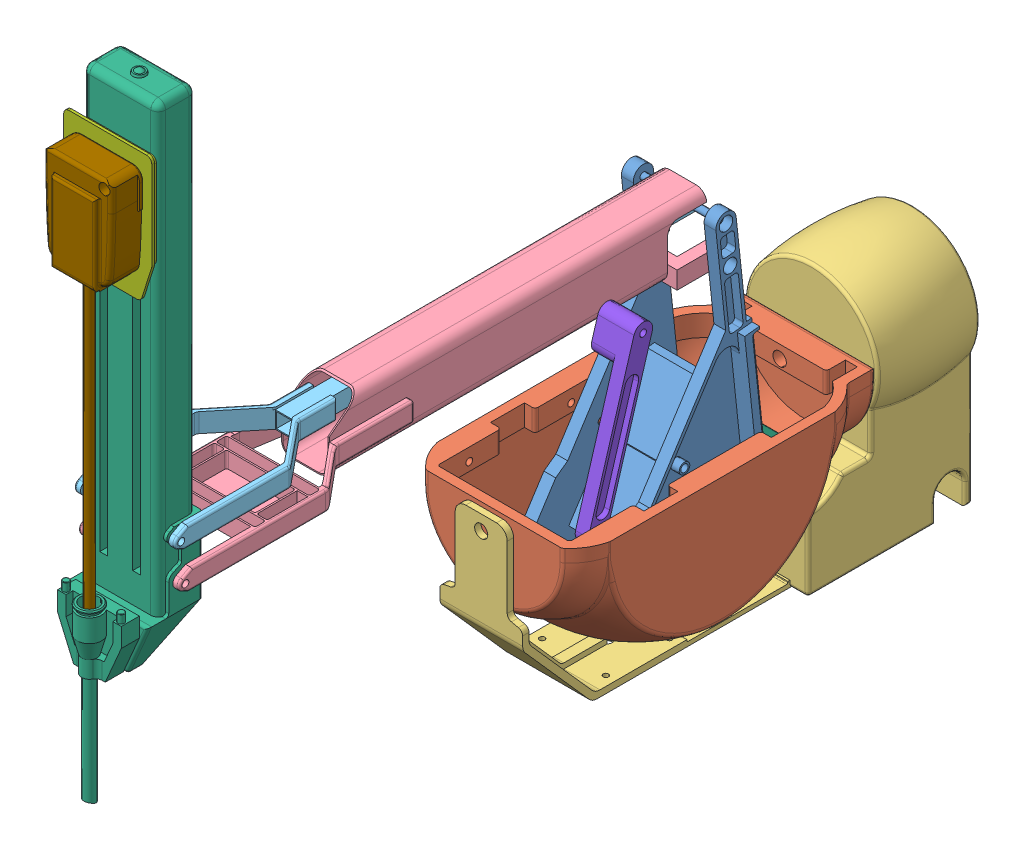
SolidWorks assembly PSM, configuration Default. Lengths in mm.
Overall size (163.88 691.06 791.55).
16 component instances, 15 part files, 45 mates.
Components (placement in the parent):
- pitch_back-1: pitch_back [Default] at (44.5 152.4 259.8) x (0 0.106301 -0.994334) z (1 0 0) size (154.33 284.37 103)
- outer_yaw-1: outer_yaw [Default] at (0 152.4 394.8) x (0 0 -1) z (1 0 0) size (296.1 145.6 163.88)
- Base-1: Base [Default] at (0 152.4 406.8) x (0 0 -1) z (1 0 0) size (406.8 219.4 134)
- pitch_bottom-1: pitch_bottom [Default] at (0 296.1053 216.8026) x (0 0 -1) z (1 0 0) size (530 58.09 95)
- pitch_top-1: pitch_top [Default] at (0 332.3985 220.6826) x (0 0 -1) z (1 0 0) size (530 18 95)
- pitch_end-1: pitch_end [Default] at (-35.75 687.2053 710.8026) x (1 0 0) z (0 -1 0) size (77.5 79.5 575.26)
- tool_holder-1: tool_holder [Default] at (-41.5 564.2053 756.0526) size (83 122 11.35)
- pitch_front-1: pitch_front [Default] at (46.5 152.4 355.8) x (0 0.958036 -0.286649) z (1 0 0) size (168 18 34)
- Tool_main-1: Tool_main [Default] at (0 543.6953 775.8026) x (1 0 0) z (0 -1 0) size (68.49 33 464)
- Tool_Wrists_Link_1-1: Tool_Wrists_Link_1 [Default] at (0 176.3953 775.8026) x (1 0 0) z (0 -1 0) size (8.32 8.32 11)
- Tool_Wrists_Shaft_Link_1_2-1: Tool_Wrists_Shaft_Link_1_2 [Default] at (3.9 167.2953 775.8026) x (0 -0.980722 0.195408) z (-1 0 0) size (1.3 1.3 8.02)
- Tool_Wristis_Small_Clip_Applier_Link_2-1: Tool_Wristis_Small_Clip_Applier_Link_2 [Default] at (0 162.1953 772.6026) x (0 1 0) z (0 0 1) size (13.22 7.35 6.88)
- Tool_Wristis_Small_Clip_Applier_shaft_Link_2_3-1: Tool_Wristis_Small_Clip_Applier_shaft_Link_2_3 [Default] at (0 158.1953 773.2026) x (0.959628 0.281272 0) z (0 0 1) size (1.3 1.3 5)
- Tool_Wristis_Small_Clip_Applier_Link_3-1: Tool_Wristis_Small_Clip_Applier_Link_3 [Default] at (0 158.1953 775.5026) x (1 0 0) z (0 0 -1) size (5 13.1 2.29)
- Tool_Wristis_Small_Clip_Applier_Link_3-2: Tool_Wristis_Small_Clip_Applier_Link_3 [Default] at (0 158.1953 776.0026) x (-1 0 0) z (0 0 1) size (5 13.1 2.29)
- counterweight-1: counterweight [Default] at (44.5 98.29 154.4714) x (0 -0.106301 0.994334) z (-1 0 0) size (25.4 25.4 89)
Mates (geometry in assembly coordinates):
- Concentric19: concentric aligned: cylinder of outer_yaw-1 through (0 152.4 80.7395) axis (0 0 1) radius 6.35; cylinder of Base-1 through (0 152.4 51.2) axis (0 0 1) radius 6.2
- Distance5: distance = 6 mm anti-aligned: plane of outer_yaw-1 through (0 152.4 394.8) normal (0 0 1); plane of Base-1 through (-56 152.4 400.8) normal (0 0 -1)
- Concentric21: concentric anti-aligned: cylinder of pitch_back-1 through (-44.5 296.1053 216.8026) axis (1 0 0) radius 6.35; cylinder of pitch_bottom-1 through (47.5 296.1053 216.8026) axis (-1 0 0) radius 3.175
- Concentric25: concentric aligned: cylinder of pitch_back-1 through (-44.5 332.3985 220.6826) axis (1 0 0) radius 6.35; cylinder of pitch_top-1 through (-47.5 332.3985 220.6826) axis (1 0 0) radius 3.175
- Concentric27: concentric anti-aligned: cylinder of pitch_back-1 through (-44.5 152.4 259.8) axis (1 0 0) radius 3.5; cylinder of outer_yaw-1 through (56.25 152.4 259.8) axis (-1 0 0) radius 3.175
- Coincident14: coincident anti-aligned: plane of Base-1 through (-56 152.4 0) normal (0 0 -1); plane of assembly through (0 0 0) normal (0 0 1)
- Coincident15: coincident anti-aligned: plane of Base-1 through (-56 0 406.8) normal (0 -1 0); plane of assembly through (0 0 0) normal (0 1 0)
- Coincident16: coincident aligned: plane of Base-1 through (0 152.4 406.8) normal (1 0 0); plane of assembly through (0 0 0) normal (1 0 0)
- Coincident17: coincident aligned: plane of pitch_back-1 through (0 152.4 259.8) normal (1 0 0); plane of outer_yaw-1 through (0 152.4 394.8) normal (1 0 0)
- Coincident18: coincident aligned: plane of pitch_back-1 through (0 152.4 259.8) normal (1 0 0); plane of pitch_bottom-1 through (0 296.1053 216.8026) normal (1 0 0)
- Coincident19: coincident aligned: plane of pitch_back-1 through (0 152.4 259.8) normal (1 0 0); plane of pitch_top-1 through (0 332.3985 220.6826) normal (1 0 0)
- Concentric29: concentric anti-aligned: cylinder of pitch_bottom-1 through (47.5 296.1053 732.8026) axis (-1 0 0) radius 3.175; cylinder of pitch_end-1 through (-43.2472 296.1053 732.8026) axis (1 0 0) radius 1.59
- Concentric30: concentric aligned: cylinder of pitch_top-1 through (-47.5 332.3985 736.6826) axis (1 0 0) radius 3.175; cylinder of pitch_end-1 through (-43.2472 332.3985 736.6826) axis (1 0 0) radius 1.5875
- Coincident20: coincident aligned: plane of pitch_bottom-1 through (0 296.1053 216.8026) normal (1 0 0); plane of pitch_end-1 through (0 687.2053 710.8026) normal (1 0 0)
- Distance7: distance = 0.4 mm anti-aligned: plane of tool_holder-1 through (-41.5 564.2053 747.2026) normal (0 0 -1); plane of pitch_end-1 through (-35.75 268.1053 746.8026) normal (0 0 1)
- Coincident21: coincident aligned: plane of pitch_end-1 through (0 687.2053 710.8026) normal (1 0 0); plane of tool_holder-1 through (0 564.2053 756.0526) normal (1 0 0)
- Concentric31: concentric aligned: cylinder of outer_yaw-1 through (56.25 152.4 355.8) axis (-1 0 0) radius 3.175; cylinder of pitch_front-1 through (58.5 152.4 355.8) axis (-1 0 0) radius 3.175
- Concentric33: concentric aligned: cylinder of pitch_bottom-1 through (47.5 296.1053 312.8026) axis (-1 0 0) radius 3.175; cylinder of pitch_front-1 through (58.5 296.1053 312.8026) axis (-1 0 0) radius 3.175
- Distance8: distance = 2 mm anti-aligned: plane of pitch_bottom-1 through (22.5 296.1053 216.8026) normal (1 0 0); plane of pitch_front-1 through (24.5 296.1053 312.8026) normal (-1 0 0)
- Concentric1: concentric: circle of Tool_main-1; circle of Tool_Wrists_Link_1-1
- Distance12: distance = 0.5 mm: plane of Tool_main-1 through (0 176.8953 775.8026) normal (0 -1 0); plane of Tool_Wrists_Link_1-1 through (0 176.3953 775.8026) normal (0 1 0)
- Parallel1: parallel: plane of Tool_main-1; plane of Tool_Wristis_Small_Clip_Applier_Link_3-1
- Concentric2: concentric anti-aligned: circle of Tool_Wrists_Link_1-1; cylinder of Tool_Wrists_Shaft_Link_1_2-1 through (-4.12 167.2953 775.8026) axis (1 0 0) radius 0.65
- Concentric3: concentric aligned: circle of Tool_Wrists_Link_1-1; cylinder of Tool_Wristis_Small_Clip_Applier_Link_2-1 through (3.6753 167.2953 775.8026) axis (-1 0 0) radius 0.65
- Distance2: distance = 7.1 mm aligned: plane of Tool_Wrists_Shaft_Link_1_2-1 through (3.9 167.2953 775.8026) normal (1 0 0); plane of Tool_Wrists_Link_1-1 through (-3.2 164.5379 771.6426) normal (1 0 0)
- Distance3: distance = 4.5 mm aligned: plane of Tool_Wristis_Small_Clip_Applier_shaft_Link_2_3-1 through (0 158.1953 773.2026) normal (0 0 -1); plane of Tool_Wristis_Small_Clip_Applier_Link_2-1 through (3.6753 156.1953 777.7026) normal (0 0 -1)
- Concentric4: concentric aligned: circle of Tool_Wristis_Small_Clip_Applier_Link_2-1; circle of Tool_Wristis_Small_Clip_Applier_Link_3-2
- Distance9: distance = 0.05 mm anti-aligned: plane of Tool_Wristis_Small_Clip_Applier_Link_3-2 through (0 158.1953 777.6526) normal (0 0 1); plane of Tool_Wristis_Small_Clip_Applier_Link_2-1 through (3.6753 156.1953 777.7026) normal (0 0 -1)
- Concentric5: concentric anti-aligned: circle of Tool_Wristis_Small_Clip_Applier_Link_2-1; circle of Tool_Wristis_Small_Clip_Applier_Link_3-1
- Distance13: distance = 0.05 mm anti-aligned: plane of Tool_Wristis_Small_Clip_Applier_Link_3-1 through (0 158.1953 773.8526) normal (0 0 -1); plane of Tool_Wristis_Small_Clip_Applier_Link_2-1 through (3.6753 156.1953 773.8026) normal (0 0 1)
- Concentric6: concentric aligned: cylinder of Tool_Wristis_Small_Clip_Applier_Link_2-1 through (0 158.1953 779.1938) axis (0 0 -1) radius 0.65; cylinder of Tool_Wristis_Small_Clip_Applier_shaft_Link_2_3-1 through (0 158.1953 778.2026) axis (0 0 -1) radius 0.65
- Concentric34: concentric aligned: cylinder of pitch_end-1 through (0 791.8005 775.8026) axis (0 1 0) radius 5.25; cylinder of Tool_main-1 through (0 176.8953 775.8026) axis (0 1 0) radius 4.2
- Distance10: distance = 416.2 mm: cylinder of Tool_Wrists_Link_1-1 through (-4.16 167.2953 775.8026) axis (1 0 0) radius 0.7; line of assembly
- Parallel5: parallel anti-aligned: plane of tool_holder-1 through (-41.5 564.2053 758.5526) normal (0 0 1); plane of Tool_main-1 through (34.1 640.8953 758.5526) normal (0 0 -1)
- yaw_zero: parallel aligned: plane of outer_yaw-1 through (81.25 2.4 518.7752) normal (1 0 0); plane of Base-1 through (39 550.3992 406.8) normal (1 0 0)
- pitch_zero: parallel aligned: plane of Base-1 through (-56 152.4 406.8) normal (0 0 1); plane of pitch_end-1 through (-35.75 268.1053 746.8026) normal (0 0 1)
- zeroinsertion: distance = 34 mm aligned: plane of tool_holder-1 through (-41.5 653.2053 758.5526) normal (0 1 0); plane of pitch_end-1 through (-35.75 687.2053 710.8026) normal (0 1 0)
- toolroll_zero: parallel aligned: plane of tool_holder-1 through (-41.5 564.2053 758.5526) normal (0 0 1); plane of Tool_Wrists_Link_1-1 through (0 176.3953 775.8026) normal (0 0 1)
- toolpitch_zero: parallel aligned: plane of Tool_Wrists_Link_1-1 through (0 176.3953 775.8026) normal (0 0 1); plane of Tool_Wristis_Small_Clip_Applier_Link_2-1 through (0 162.1953 772.6026) normal (0 0 1)
- zero_jaw1: parallel anti-aligned: plane of Tool_Wristis_Small_Clip_Applier_Link_2-1 through (0 162.1953 772.6026) normal (-1 0 0); plane of Tool_Wristis_Small_Clip_Applier_Link_3-1 through (0 147.5953 776.1026) normal (1 0 0)
- zero_jaw2: parallel anti-aligned: plane of Tool_Wristis_Small_Clip_Applier_Link_3-1 through (-1.5 147.5953 773.9026) normal (-1 0 0); plane of Tool_Wristis_Small_Clip_Applier_Link_3-2 through (1.5 147.5953 777.6026) normal (1 0 0)
- Distance11: distance = 3.2 mm aligned: plane of Tool_Wristis_Small_Clip_Applier_Link_2-1 through (0 162.1953 772.6026) normal (-1 0 0); plane of Tool_Wrists_Link_1-1 through (3.2 164.5379 771.6426) normal (-1 0 0)
- Distance14: distance = 1 mm anti-aligned: plane of pitch_back-1 through (-44.5 160.1153 187.6314) normal (0 0.106301 -0.994334); plane of counterweight-1 through (-44.5016 95.5899 179.7275) normal (0 -0.106301 0.994334)
- Coincident23: coincident aligned: plane of pitch_back-1 through (44.5 152.4 259.8) normal (1 0 0); plane of counterweight-1 through (44.5 98.29 154.4714) normal (1 0 0)
- counterweight_zero: distance = 20 mm: moEndPointRef_w of pitch_back-1; plane of counterweight-1 through (-44.5016 98.29 154.4714) normal (0 -0.994334 -0.106301)
